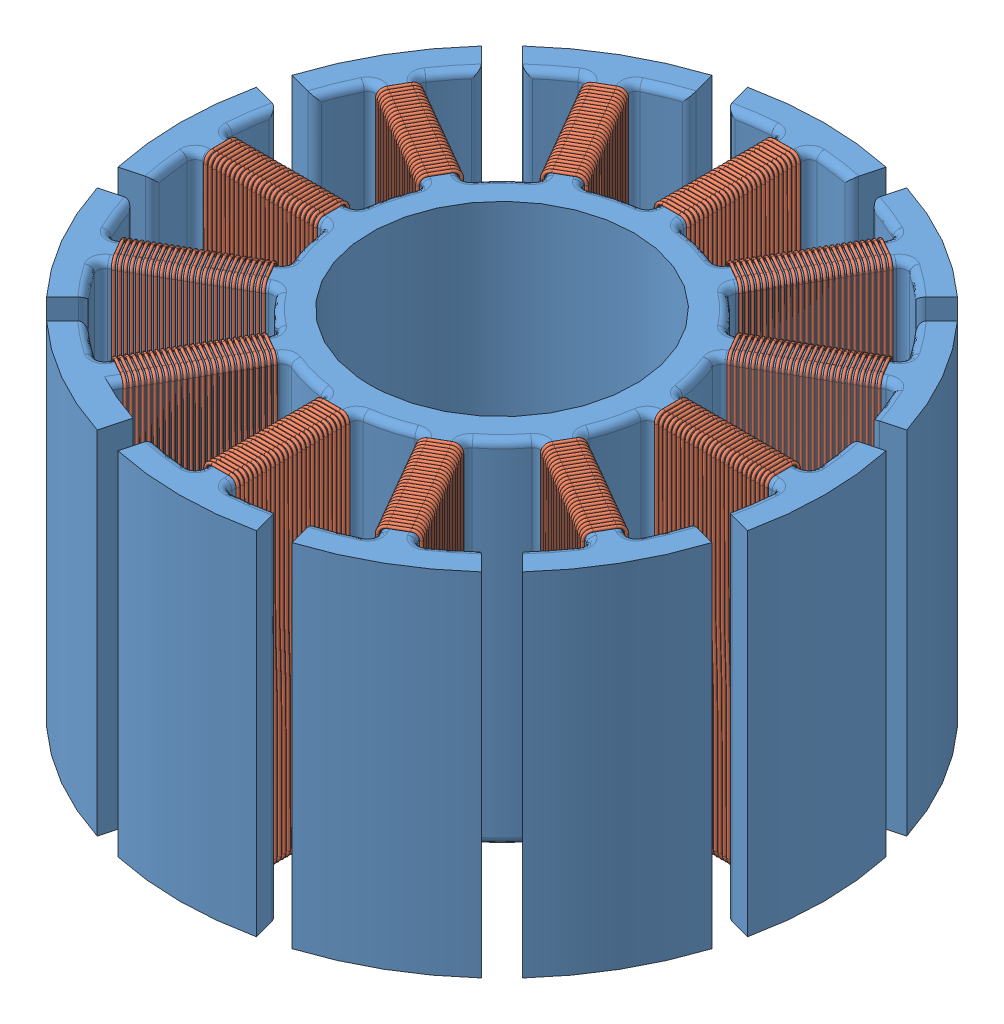
SolidWorks assembly Stator, configuration Default. Lengths in mm.
Overall size (22 12.2 22).
13 component instances, 2 part files, 6 mates.
Components (placement in the parent):
- Stator_Steelcore-1: Stator_Steelcore [Default] at origin size (22 12.05 22)
- Stator_Coil-1: Stator_Coil [Default] at (-2.8504 6 4.9371) x (0.5 0 -0.866025) z (0.866025 0 0.5) size (4.11 12.2 1.21)
- Stator_Coil-2: Stator_Coil [Default] at (0 6 5.7009) x (0 0 -1) z (1 0 0) size (4.11 12.2 1.21)
- Stator_Coil-3: Stator_Coil [Default] at (2.8504 6 4.9371) x (-0.5 0 -0.866025) z (0.866025 0 -0.5) size (4.11 12.2 1.21)
- Stator_Coil-4: Stator_Coil [Default] at (4.9371 6 2.8504) x (-0.866025 0 -0.5) z (0.5 0 -0.866025) size (4.11 12.2 1.21)
- Stator_Coil-5: Stator_Coil [Default] at (5.7009 6 0) x (-1 0 0) z (0 0 -1) size (4.11 12.2 1.21)
- Stator_Coil-6: Stator_Coil [Default] at (4.9371 6 -2.8504) x (-0.866025 0 0.5) z (-0.5 0 -0.866025) size (4.11 12.2 1.21)
- Stator_Coil-7: Stator_Coil [Default] at (2.8504 6 -4.9371) x (-0.5 0 0.866025) z (-0.866025 0 -0.5) size (4.11 12.2 1.21)
- Stator_Coil-8: Stator_Coil [Default] at (0 6 -5.7009) x (0 0 1) z (-1 0 0) size (4.11 12.2 1.21)
- Stator_Coil-9: Stator_Coil [Default] at (-2.8504 6 -4.9371) x (0.5 0 0.866025) z (-0.866025 0 0.5) size (4.11 12.2 1.21)
- Stator_Coil-10: Stator_Coil [Default] at (-4.9371 6 -2.8504) x (0.866025 0 0.5) z (-0.5 0 0.866025) size (4.11 12.2 1.21)
- Stator_Coil-11: Stator_Coil [Default] at (-5.7009 6 0) size (4.11 12.2 1.21)
- Stator_Coil-12: Stator_Coil [Default] at (-4.9371 6 2.8504) x (0.866025 0 -0.5) z (0.5 0 0.866025) size (4.11 12.2 1.21)
Mates (geometry in assembly coordinates):
- Coincident1: coincident aligned: plane of Stator_Steelcore-1 through (0 0 0) normal (0 1 0); plane of assembly through (0 0 0) normal (0 1 0)
- Coincident2: coincident: plane of Stator_Steelcore-1 through (0 0 0) normal (0 0 1); plane of assembly through (0 0 0) normal (0 0 1)
- Coincident3: coincident: plane of Stator_Steelcore-1 through (0 0 0) normal (1 0 0); plane of assembly through (0 0 0) normal (1 0 0)
- Distance1: distance = 0.25 mm: plane of Stator_Coil-1 through (-2.8504 6 4.9371) normal (0.866025 0 0.5); line of Stator_Steelcore-1 through (-4.7819 12 8.7825) axis (0.5 0 -0.866025)
- Distance2: distance = 6 mm aligned: plane of Stator_Coil-1; plane of Stator_Steelcore-1 through (0 12 0) normal (0 1 0)
- Coincident7: coincident: point of Stator_Steelcore-1; plane of Stator_Coil-1 through (-2.8504 6 4.9371) normal (0.5 0 -0.866025)
